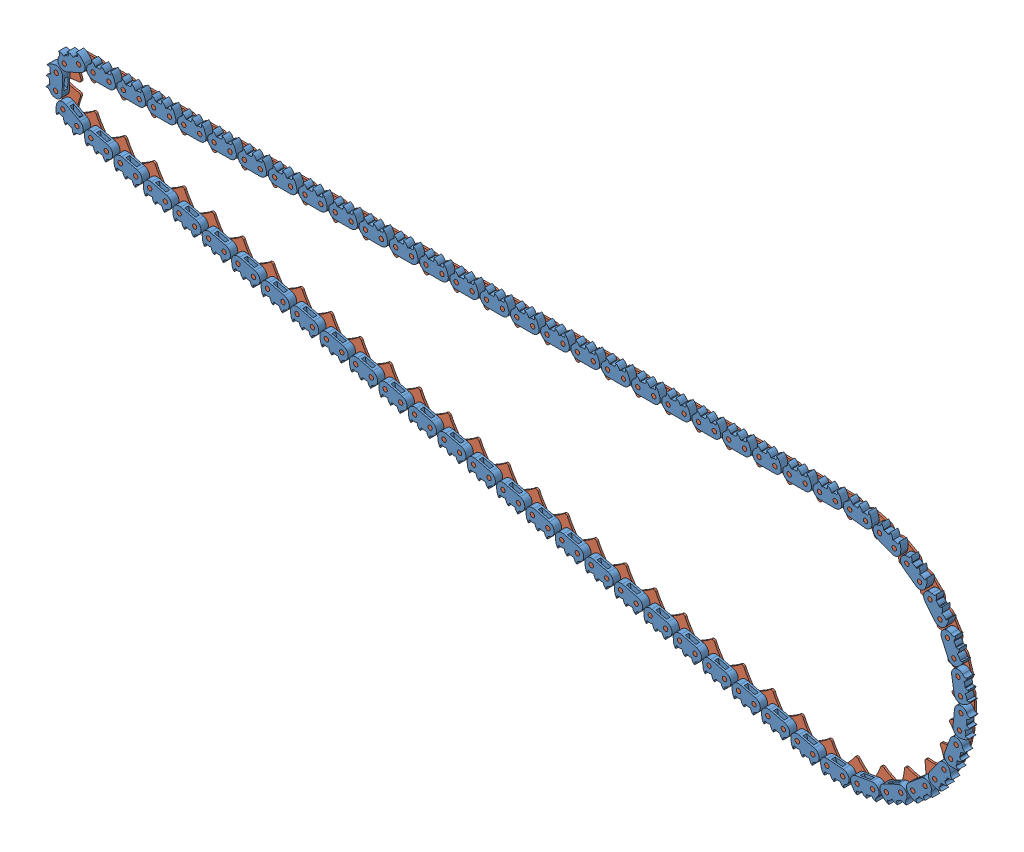
SolidWorks assembly Assem5, configuration Default. Lengths in mm.
Overall size (252.06 69.71 2.5).
133 component instances, 3 part files, 2 mates.
Components (placement in the parent):
- Spline-1: Spline [Default] at (87.6517 162.9849 185.7107) size (246.88 63.94 0)
- Teeth-1: Teeth [Default] at (181.5058 99.5627 184.7107) x (-0.972524 0.232803 0) z (0 0 1) size (7.83 4.36 2)
- Inner Part-1: Inner Part [Default] at (181.5247 99.6486 184.2107) x (-0.980073 0.198639 0) z (0 0 1) size (7.41 6.1 2.5)
- Teeth-2: Teeth [Default] at (189.7233 98.8599 184.7107) x (-0.997209 0.074661 0) z (0 0 1) size (7.83 4.36 2)
- Teeth-3: Teeth [Default] at (197.8558 100.5056 184.7107) x (-0.983309 -0.181945 0) z (0 0 1) size (7.83 4.36 2)
- Teeth-4: Teeth [Default] at (205.3003 104.1696 184.7107) x (-0.904466 -0.426545 0) z (0 0 1) size (7.83 4.36 2)
- Teeth-5: Teeth [Default] at (211.5647 109.6104 184.7107) x (-0.765832 -0.643041 0) z (0 0 1) size (7.83 4.36 2)
- Teeth-6: Teeth [Default] at (216.2339 116.4693 184.7107) x (-0.576468 -0.81712 0) z (0 0 1) size (7.83 4.36 2)
- Teeth-7: Teeth [Default] at (218.9979 124.2929 184.7107) x (-0.348814 -0.937192 0) z (0 0 1) size (7.83 4.36 2)
- Teeth-8: Teeth [Default] at (219.6722 132.563 184.7107) x (-0.09792 -0.995194 0) z (0 0 1) size (7.83 4.36 2)
- Teeth-9: Teeth [Default] at (218.2115 140.7309 184.7107) x (0.159544 -0.987191 0) z (0 0 1) size (7.83 4.36 2)
- Teeth-10: Teeth [Default] at (214.7128 148.2548 184.7107) x (0.406419 -0.913687 0) z (0 0 1) size (7.83 4.36 2)
- Teeth-11: Teeth [Default] at (209.4089 154.6358 184.7107) x (0.626264 -0.779611 0) z (0 0 1) size (7.83 4.36 2)
- Teeth-12: Teeth [Default] at (202.652 159.4517 184.7107) x (0.804501 -0.593952 0) z (0 0 1) size (7.83 4.36 2)
- Teeth-13: Teeth [Default] at (194.8904 162.3849 184.7107) x (0.92939 -0.369099 0) z (0 0 1) size (7.83 4.36 2)
- Teeth-14: Teeth [Default] at (186.6375 163.2425 184.7107) x (0.992778 -0.119966 0) z (0 0 1) size (7.83 4.36 2)
- Teeth-15: Teeth [Default] at (178.3741 162.9849 184.7107) size (7.83 4.36 2)
- Teeth-16: Teeth [Default] at (170.1286 162.9849 184.7107) size (7.83 4.36 2)
- Teeth-17: Teeth [Default] at (161.8831 162.9849 184.7107) size (7.83 4.36 2)
- Teeth-18: Teeth [Default] at (153.6376 162.9849 184.7107) size (7.83 4.36 2)
- Teeth-19: Teeth [Default] at (145.3921 162.9849 184.7107) size (7.83 4.36 2)
- Teeth-20: Teeth [Default] at (137.1466 162.9849 184.7107) size (7.83 4.36 2)
- Teeth-21: Teeth [Default] at (128.9011 162.9849 184.7107) size (7.83 4.36 2)
- Teeth-22: Teeth [Default] at (120.6556 162.9849 184.7107) size (7.83 4.36 2)
- Teeth-23: Teeth [Default] at (112.4101 162.9849 184.7107) size (7.83 4.36 2)
- Teeth-24: Teeth [Default] at (104.1646 162.9849 184.7107) size (7.83 4.36 2)
- Teeth-25: Teeth [Default] at (95.9191 162.9849 184.7107) size (7.83 4.36 2)
- Teeth-26: Teeth [Default] at (87.6736 162.9849 184.7107) size (7.83 4.36 2)
- Teeth-27: Teeth [Default] at (79.4281 162.9849 184.7107) size (7.83 4.36 2)
- Teeth-28: Teeth [Default] at (71.1826 162.9849 184.7107) size (7.83 4.36 2)
- Teeth-29: Teeth [Default] at (62.9371 162.9849 184.7107) size (7.83 4.36 2)
- Teeth-30: Teeth [Default] at (54.6916 162.9849 184.7107) size (7.83 4.36 2)
- Teeth-31: Teeth [Default] at (46.4461 162.9849 184.7107) size (7.83 4.36 2)
- Teeth-32: Teeth [Default] at (38.2006 162.9849 184.7107) size (7.83 4.36 2)
- Teeth-33: Teeth [Default] at (29.9551 162.9849 184.7107) size (7.83 4.36 2)
- Teeth-34: Teeth [Default] at (21.7096 162.9849 184.7107) size (7.83 4.36 2)
- Teeth-35: Teeth [Default] at (13.4641 162.9849 184.7107) size (7.83 4.36 2)
- Teeth-36: Teeth [Default] at (5.2186 162.9849 184.7107) size (7.83 4.36 2)
- Teeth-37: Teeth [Default] at (-3.0269 162.9849 184.7107) size (7.83 4.36 2)
- Teeth-38: Teeth [Default] at (-11.2724 162.9849 184.7107) size (7.83 4.36 2)
- Teeth-39: Teeth [Default] at (-19.5178 162.9849 184.7107) size (7.83 4.36 2)
- Teeth-40: Teeth [Default] at (-27.1586 160.1091 184.7107) x (0.91178 0.410678 0) z (0 0 1) size (7.83 4.36 2)
- Teeth-41: Teeth [Default] at (-27.2697 151.0467 184.7107) x (0.033254 0.999447 0) z (0 0 1) size (7.83 4.36 2)
- Teeth-42: Teeth [Default] at (-19.1843 146.9516 184.7107) x (-0.882376 0.470546 0) z (0 0 1) size (7.83 4.36 2)
- Teeth-43: Teeth [Default] at (-10.9386 145.6301 184.7107) x (-0.972524 0.232803 0) z (0 0 1) size (7.83 4.36 2)
- Teeth-44: Teeth [Default] at (-2.9196 143.7105 184.7107) x (-0.972524 0.232803 0) z (0 0 1) size (7.83 4.36 2)
- Teeth-45: Teeth [Default] at (5.0993 141.7909 184.7107) x (-0.972524 0.232803 0) z (0 0 1) size (7.83 4.36 2)
- Teeth-46: Teeth [Default] at (13.1183 139.8714 184.7107) x (-0.972524 0.232803 0) z (0 0 1) size (7.83 4.36 2)
- Teeth-47: Teeth [Default] at (21.1372 137.9518 184.7107) x (-0.972524 0.232803 0) z (0 0 1) size (7.83 4.36 2)
- Teeth-48: Teeth [Default] at (29.1561 136.0322 184.7107) x (-0.972524 0.232803 0) z (0 0 1) size (7.83 4.36 2)
- Teeth-49: Teeth [Default] at (37.1751 134.1126 184.7107) x (-0.972524 0.232803 0) z (0 0 1) size (7.83 4.36 2)
- Teeth-50: Teeth [Default] at (45.194 132.1931 184.7107) x (-0.972524 0.232803 0) z (0 0 1) size (7.83 4.36 2)
- Teeth-51: Teeth [Default] at (53.213 130.2735 184.7107) x (-0.972524 0.232803 0) z (0 0 1) size (7.83 4.36 2)
- Teeth-52: Teeth [Default] at (61.2319 128.3539 184.7107) x (-0.972524 0.232803 0) z (0 0 1) size (7.83 4.36 2)
- Teeth-53: Teeth [Default] at (69.2508 126.4343 184.7107) x (-0.972524 0.232803 0) z (0 0 1) size (7.83 4.36 2)
- Teeth-54: Teeth [Default] at (77.2698 124.5147 184.7107) x (-0.972524 0.232803 0) z (0 0 1) size (7.83 4.36 2)
- Teeth-55: Teeth [Default] at (85.2887 122.5952 184.7107) x (-0.972524 0.232803 0) z (0 0 1) size (7.83 4.36 2)
- Teeth-56: Teeth [Default] at (93.3077 120.6756 184.7107) x (-0.972524 0.232803 0) z (0 0 1) size (7.83 4.36 2)
- Teeth-57: Teeth [Default] at (101.3266 118.756 184.7107) x (-0.972524 0.232803 0) z (0 0 1) size (7.83 4.36 2)
- Teeth-58: Teeth [Default] at (109.3456 116.8364 184.7107) x (-0.972524 0.232803 0) z (0 0 1) size (7.83 4.36 2)
- Teeth-59: Teeth [Default] at (117.3645 114.9168 184.7107) x (-0.972524 0.232803 0) z (0 0 1) size (7.83 4.36 2)
- Teeth-60: Teeth [Default] at (125.3834 112.9973 184.7107) x (-0.972524 0.232803 0) z (0 0 1) size (7.83 4.36 2)
- Teeth-61: Teeth [Default] at (133.4024 111.0777 184.7107) x (-0.972524 0.232803 0) z (0 0 1) size (7.83 4.36 2)
- Teeth-62: Teeth [Default] at (141.4213 109.1581 184.7107) x (-0.972524 0.232803 0) z (0 0 1) size (7.83 4.36 2)
- Teeth-63: Teeth [Default] at (149.4403 107.2385 184.7107) x (-0.972524 0.232803 0) z (0 0 1) size (7.83 4.36 2)
- Teeth-64: Teeth [Default] at (157.4592 105.3189 184.7107) x (-0.972524 0.232803 0) z (0 0 1) size (7.83 4.36 2)
- Teeth-65: Teeth [Default] at (165.4781 103.3994 184.7107) x (-0.972524 0.232803 0) z (0 0 1) size (7.83 4.36 2)
- Teeth-66: Teeth [Default] at (173.4971 101.4798 184.7107) x (-0.972524 0.232803 0) z (0 0 1) size (7.83 4.36 2)
- Inner Part-2: Inner Part [Default] at (189.7266 99.1839 184.2107) x (-0.998536 -0.054094 0) z (0 0 1) size (7.41 6.1 2.5)
- Inner Part-3: Inner Part [Default] at (197.7764 100.8197 184.2107) x (-0.95178 -0.306782 0) z (0 0 1) size (7.41 6.1 2.5)
- Inner Part-4: Inner Part [Default] at (205.1435 104.4531 184.2107) x (-0.842143 -0.539254 0) z (0 0 1) size (7.41 6.1 2.5)
- Inner Part-5: Inner Part [Default] at (211.3406 109.8448 184.2107) x (-0.676785 -0.736181 0) z (0 0 1) size (7.41 6.1 2.5)
- Inner Part-6: Inner Part [Default] at (215.9574 116.6389 184.2107) x (-0.466538 -0.884501 0) z (0 0 1) size (7.41 6.1 2.5)
- Inner Part-7: Inner Part [Default] at (218.687 124.3863 184.2107) x (-0.225256 -0.9743 0) z (0 0 1) size (7.41 6.1 2.5)
- Inner Part-8: Inner Part [Default] at (219.3477 132.5738 184.2107) x (0.031066 -0.999517 0) z (0 0 1) size (7.41 6.1 2.5)
- Inner Part-9: Inner Part [Default] at (217.8949 140.6585 184.2107) x (0.285363 -0.958419 0) z (0 0 1) size (7.41 6.1 2.5)
- Inner Part-10: Inner Part [Default] at (214.4253 148.104 184.2107) x (0.520687 -0.853747 0) z (0 0 1) size (7.41 6.1 2.5)
- Inner Part-11: Inner Part [Default] at (209.1695 154.4167 184.2107) x (0.721394 -0.692525 0) z (0 0 1) size (7.41 6.1 2.5)
- Inner Part-12: Inner Part [Default] at (202.4766 159.179 184.2107) x (0.874214 -0.48554 0) z (0 0 1) size (7.41 6.1 2.5)
- Inner Part-13: Inner Part [Default] at (194.7904 162.0766 184.2107) x (0.969127 -0.246563 0) z (0 0 1) size (7.41 6.1 2.5)
- Inner Part-14: Inner Part [Default] at (186.6195 162.9691 184.2107) x (0.999936 -0.011287 0) z (0 0 1) size (7.41 6.1 2.5)
- Inner Part-15: Inner Part [Default] at (178.3741 162.9849 184.2107) size (7.41 6.1 2.5)
- Inner Part-16: Inner Part [Default] at (170.1286 162.9849 184.2107) size (7.41 6.1 2.5)
- Inner Part-17: Inner Part [Default] at (161.8831 162.9849 184.2107) size (7.41 6.1 2.5)
- Inner Part-18: Inner Part [Default] at (153.6376 162.9849 184.2107) size (7.41 6.1 2.5)
- Inner Part-19: Inner Part [Default] at (145.3921 162.9849 184.2107) size (7.41 6.1 2.5)
- Inner Part-20: Inner Part [Default] at (137.1466 162.9849 184.2107) size (7.41 6.1 2.5)
- Inner Part-21: Inner Part [Default] at (128.9011 162.9849 184.2107) size (7.41 6.1 2.5)
- Inner Part-22: Inner Part [Default] at (120.6556 162.9849 184.2107) size (7.41 6.1 2.5)
- Inner Part-23: Inner Part [Default] at (112.4101 162.9849 184.2107) size (7.41 6.1 2.5)
- Inner Part-24: Inner Part [Default] at (104.1646 162.9849 184.2107) size (7.41 6.1 2.5)
- Inner Part-25: Inner Part [Default] at (95.9191 162.9849 184.2107) size (7.41 6.1 2.5)
- Inner Part-26: Inner Part [Default] at (87.6736 162.9849 184.2107) size (7.41 6.1 2.5)
- Inner Part-27: Inner Part [Default] at (79.4281 162.9849 184.2107) size (7.41 6.1 2.5)
- Inner Part-28: Inner Part [Default] at (71.1826 162.9849 184.2107) size (7.41 6.1 2.5)
- Inner Part-29: Inner Part [Default] at (62.9371 162.9849 184.2107) size (7.41 6.1 2.5)
- Inner Part-30: Inner Part [Default] at (54.6916 162.9849 184.2107) size (7.41 6.1 2.5)
- Inner Part-31: Inner Part [Default] at (46.4461 162.9849 184.2107) size (7.41 6.1 2.5)
- Inner Part-32: Inner Part [Default] at (38.2006 162.9849 184.2107) size (7.41 6.1 2.5)
- Inner Part-33: Inner Part [Default] at (29.9551 162.9849 184.2107) size (7.41 6.1 2.5)
- Inner Part-34: Inner Part [Default] at (21.7096 162.9849 184.2107) size (7.41 6.1 2.5)
- Inner Part-35: Inner Part [Default] at (13.4641 162.9849 184.2107) size (7.41 6.1 2.5)
- Inner Part-36: Inner Part [Default] at (5.2186 162.9849 184.2107) size (7.41 6.1 2.5)
- Inner Part-37: Inner Part [Default] at (-3.0269 162.9849 184.2107) size (7.41 6.1 2.5)
- Inner Part-38: Inner Part [Default] at (-11.2724 162.9849 184.2107) size (7.41 6.1 2.5)
- Inner Part-39: Inner Part [Default] at (-19.5175 162.9445 184.2107) x (0.999871 0.016056 0) z (0 0 1) size (7.41 6.1 2.5)
- Inner Part-40: Inner Part [Default] at (-26.265 159.0522 184.2107) x (0.556591 0.830787 0) z (0 0 1) size (7.41 6.1 2.5)
- Inner Part-41: Inner Part [Default] at (-25.9269 151.3831 184.2107) x (-0.500511 0.86573 0) z (0 0 1) size (7.41 6.1 2.5)
- Inner Part-42: Inner Part [Default] at (-18.9575 147.5497 184.2107) x (-0.972524 0.232803 0) z (0 0 1) size (7.41 6.1 2.5)
- Inner Part-43: Inner Part [Default] at (-10.9386 145.6301 184.2107) x (-0.972524 0.232803 0) z (0 0 1) size (7.41 6.1 2.5)
- Inner Part-44: Inner Part [Default] at (-2.9196 143.7105 184.2107) x (-0.972524 0.232803 0) z (0 0 1) size (7.41 6.1 2.5)
- Inner Part-45: Inner Part [Default] at (5.0993 141.7909 184.2107) x (-0.972524 0.232803 0) z (0 0 1) size (7.41 6.1 2.5)
- Inner Part-46: Inner Part [Default] at (13.1183 139.8714 184.2107) x (-0.972524 0.232803 0) z (0 0 1) size (7.41 6.1 2.5)
- Inner Part-47: Inner Part [Default] at (21.1372 137.9518 184.2107) x (-0.972524 0.232803 0) z (0 0 1) size (7.41 6.1 2.5)
- Inner Part-48: Inner Part [Default] at (29.1561 136.0322 184.2107) x (-0.972524 0.232803 0) z (0 0 1) size (7.41 6.1 2.5)
- Inner Part-49: Inner Part [Default] at (37.1751 134.1126 184.2107) x (-0.972524 0.232803 0) z (0 0 1) size (7.41 6.1 2.5)
- Inner Part-50: Inner Part [Default] at (45.194 132.1931 184.2107) x (-0.972524 0.232803 0) z (0 0 1) size (7.41 6.1 2.5)
- Inner Part-51: Inner Part [Default] at (53.213 130.2735 184.2107) x (-0.972524 0.232803 0) z (0 0 1) size (7.41 6.1 2.5)
- Inner Part-52: Inner Part [Default] at (61.2319 128.3539 184.2107) x (-0.972524 0.232803 0) z (0 0 1) size (7.41 6.1 2.5)
- Inner Part-53: Inner Part [Default] at (69.2508 126.4343 184.2107) x (-0.972524 0.232803 0) z (0 0 1) size (7.41 6.1 2.5)
- Inner Part-54: Inner Part [Default] at (77.2698 124.5147 184.2107) x (-0.972524 0.232803 0) z (0 0 1) size (7.41 6.1 2.5)
- Inner Part-55: Inner Part [Default] at (85.2887 122.5952 184.2107) x (-0.972524 0.232803 0) z (0 0 1) size (7.41 6.1 2.5)
- Inner Part-56: Inner Part [Default] at (93.3077 120.6756 184.2107) x (-0.972524 0.232803 0) z (0 0 1) size (7.41 6.1 2.5)
- Inner Part-57: Inner Part [Default] at (101.3266 118.756 184.2107) x (-0.972524 0.232803 0) z (0 0 1) size (7.41 6.1 2.5)
- Inner Part-58: Inner Part [Default] at (109.3456 116.8364 184.2107) x (-0.972524 0.232803 0) z (0 0 1) size (7.41 6.1 2.5)
- Inner Part-59: Inner Part [Default] at (117.3645 114.9168 184.2107) x (-0.972524 0.232803 0) z (0 0 1) size (7.41 6.1 2.5)
- Inner Part-60: Inner Part [Default] at (125.3834 112.9973 184.2107) x (-0.972524 0.232803 0) z (0 0 1) size (7.41 6.1 2.5)
- Inner Part-61: Inner Part [Default] at (133.4024 111.0777 184.2107) x (-0.972524 0.232803 0) z (0 0 1) size (7.41 6.1 2.5)
- Inner Part-62: Inner Part [Default] at (141.4213 109.1581 184.2107) x (-0.972524 0.232803 0) z (0 0 1) size (7.41 6.1 2.5)
- Inner Part-63: Inner Part [Default] at (149.4403 107.2385 184.2107) x (-0.972524 0.232803 0) z (0 0 1) size (7.41 6.1 2.5)
- Inner Part-64: Inner Part [Default] at (157.4592 105.3189 184.2107) x (-0.972524 0.232803 0) z (0 0 1) size (7.41 6.1 2.5)
- Inner Part-65: Inner Part [Default] at (165.4781 103.3994 184.2107) x (-0.972524 0.232803 0) z (0 0 1) size (7.41 6.1 2.5)
- Inner Part-66: Inner Part [Default] at (173.4971 101.4798 184.2107) x (-0.972524 0.232803 0) z (0 0 1) size (7.41 6.1 2.5)
Mates (geometry in assembly coordinates):
- Parallel1: parallel: line of Spline-1 through (-19.9458 162.9849 185.7107) axis (1 0 0); plane of assembly
- Lock1: lock: unknown of Spline-1
